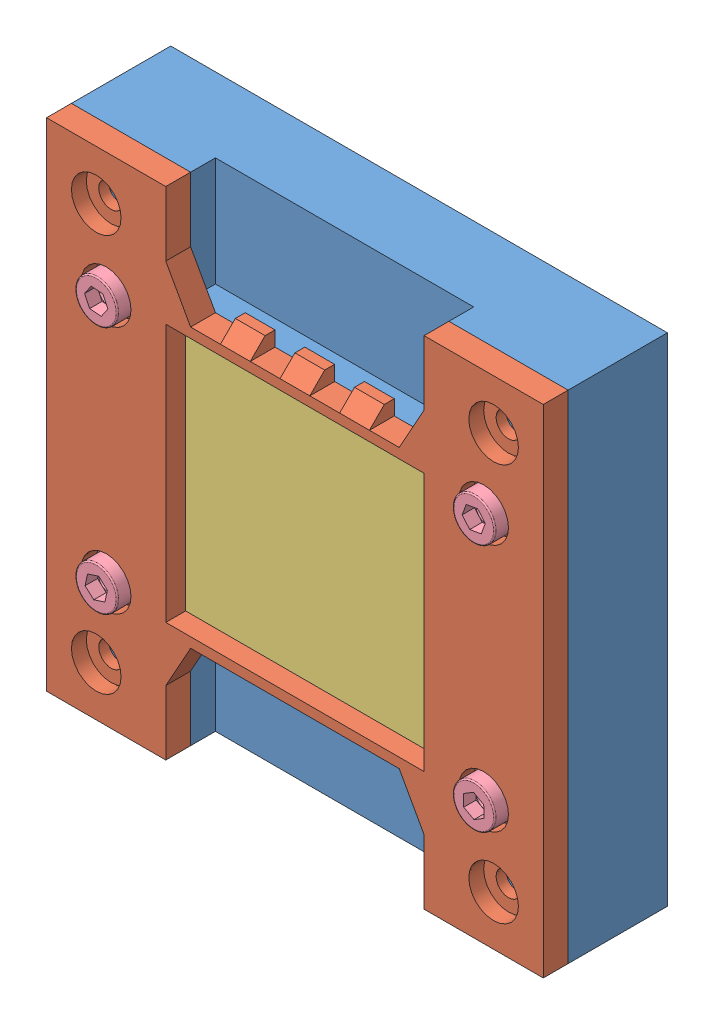
SolidWorks assembly wärmetauscher, configuration Standard. Lengths in mm.
Overall size (100 100 27).
7 component instances, 4 part files, 14 mates.
Components (placement in the parent):
- wärmetauscher-unten-1: wärmetauscher-unten [Standard] at (1.4741 -5.4358 0) size (100 100 20)
- wärmetauscher-oben-1: wärmetauscher-oben [Standard] at (1.4741 -5.4358 20) size (100 100 5)
- wasserelement-1: wasserelement [Standard] at (1.4741 -5.4358 22) x (-1 0 0) z (0 0 -1) size (50 50 17)
- Socket Head Cap Screw_ISO-8: Socket Head Cap Screw_ISO [ISO 4762 M5 x 8 --- 8N] at (39.4741 19.5642 27) x (0 0 -1) z (0.767578 0.640956 0) size (13 8.5 8.5)
- Socket Head Cap Screw_ISO-9: Socket Head Cap Screw_ISO [ISO 4762 M5 x 8 --- 8N] at (39.4741 -30.4358 27) x (0 0 -1) z (0.520258 -0.854009 0) size (13 8.5 8.5)
- Socket Head Cap Screw_ISO-10: Socket Head Cap Screw_ISO [ISO 4762 M5 x 8 --- 8N] at (-36.5259 -30.4358 27) x (0 0 -1) z (0.670993 0.741464 0) size (13 8.5 8.5)
- Socket Head Cap Screw_ISO-12: Socket Head Cap Screw_ISO [ISO 4762 M5 x 8 --- 8N] at (-36.5259 19.5642 27) x (0 0 -1) z (0.826163 -0.563431 0) size (13 8.5 8.5)
Mates (geometry in assembly coordinates):
- Deckungsgleich1: coincident anti-aligned: plane of wärmetauscher-unten-1 through (-48.5259 -55.4358 20) normal (0 0 1); plane of wärmetauscher-oben-1 through (-48.5259 -55.4358 20) normal (0 0 -1)
- Deckungsgleich2: coincident aligned: axis of wärmetauscher-unten-1; axis of wärmetauscher-oben-1
- Deckungsgleich3: coincident aligned: axis of wärmetauscher-unten-1; axis of wärmetauscher-oben-1
- Deckungsgleich4: coincident anti-aligned: plane of wärmetauscher-unten-1 through (-24.5259 -31.4358 5) normal (0 0 1); plane of wasserelement-1 through (26.4741 -30.4358 5) normal (0 0 -1)
- Abstand1: distance = 1 mm: line of wärmetauscher-unten-1; line of wasserelement-1
- Abstand2: distance = 1 mm: line of wärmetauscher-unten-1; line of wasserelement-1
- Konzentrisch131: concentric aligned: cylinder of wärmetauscher-oben-1; cylinder of Socket Head Cap Screw_ISO-8
- Deckungsgleich171: coincident anti-aligned: plane of Socket Head Cap Screw_ISO-8; plane of wärmetauscher-oben-1 through (39.4741 19.5642 22) normal (0 0 1)
- Konzentrisch141: concentric aligned: cylinder of wärmetauscher-oben-1; cylinder of Socket Head Cap Screw_ISO-9
- Deckungsgleich181: coincident anti-aligned: plane of Socket Head Cap Screw_ISO-9; plane of wärmetauscher-oben-1 through (39.4741 -30.4358 22) normal (0 0 1)
- Konzentrisch151: concentric aligned: cylinder of wärmetauscher-oben-1; cylinder of Socket Head Cap Screw_ISO-10
- Deckungsgleich191: coincident anti-aligned: plane of Socket Head Cap Screw_ISO-10; plane of wärmetauscher-oben-1 through (-36.5259 -30.4358 22) normal (0 0 1)
- Konzentrisch161: concentric aligned: cylinder of wärmetauscher-oben-1; cylinder of Socket Head Cap Screw_ISO-12
- Deckungsgleich201: coincident anti-aligned: plane of Socket Head Cap Screw_ISO-12; circle of wärmetauscher-oben-1 centre (-36.5259 19.5642 22) axis (0 0 1)
